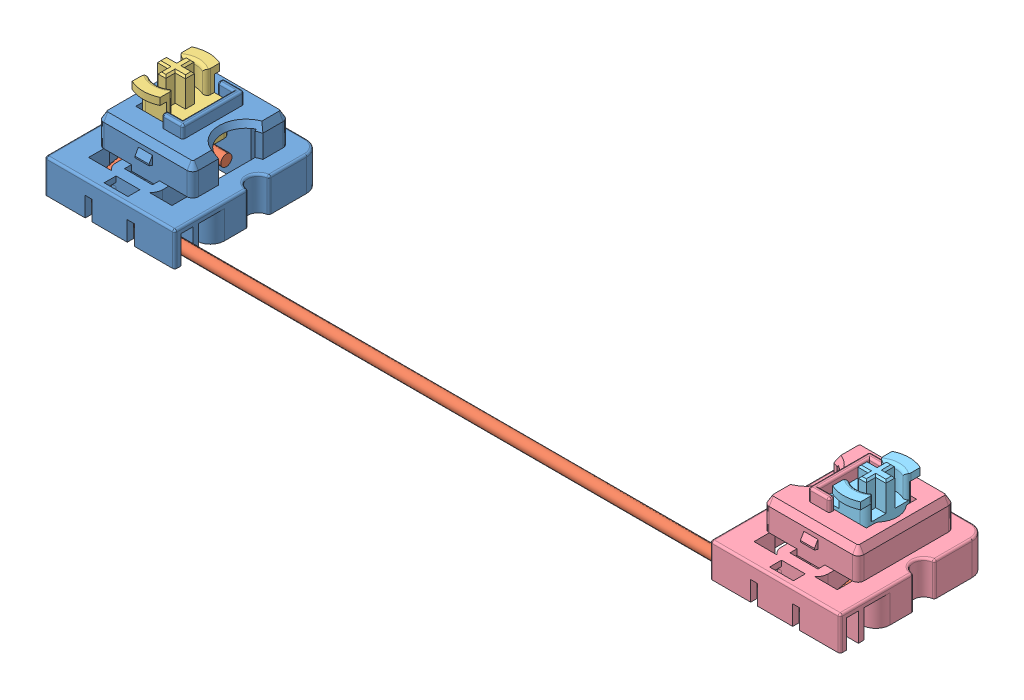
SolidWorks assembly Stabilizers, configuration Default. Lengths in mm.
Overall size (113.55 13.31 20.85).
5 component instances, 5 part files, 13 mates.
Components (placement in the parent):
- Stabilizer Housing Left-4: Stabilizer Housing Left [Default] at (-18.6144 -12.306 -7.1662) size (18.55 10.8 20.85)
- Stabilizer Wire-2: Stabilizer Wire [Default] at (28.8856 -14.606 3.0838) x (1 0 0) z (0 -0.226827 0.973935) size (106 1.6 13.1)
- Stabilizer Plunger Left-1: Stabilizer Plunger Left [Default] at (-21.1144 -13.7975 -7.1662) size (6.4 10.8 9.4)
- Stabilizer Housing Right-1: Stabilizer Housing Right [Default] at (76.3856 -12.306 -7.1662) size (18.55 10.8 20.85)
- Stabilizer Plunger Right-1: Stabilizer Plunger Right [Default] at (78.8856 -13.7975 -7.1662) size (6.4 10.8 9.4)
Mates (geometry in assembly coordinates):
- Tangent2: tangent: plane of assembly; cylinder of assembly; plane of Stabilizer Housing Left-4 through (-18.6144 -13.806 -7.1662) normal (0 -1 0); cylinder of Stabilizer Wire-2 through (79.4856 -14.606 3.0838) axis (-1 0 0) radius 0.8
- Distance3: distance = 47.5 mm: plane of assembly; plane of assembly; plane of Stabilizer Wire-2 through (28.8856 -14.606 3.0838) normal (1 0 0); plane of Stabilizer Housing Left-4 through (-18.6144 -12.306 -7.1662) normal (1 0 0)
- Tangent3: tangent: plane of assembly; cylinder of assembly; plane of Stabilizer Housing Left-4 through (-9.3394 -34.8778 3.8838) normal (0 0 -1); cylinder of Stabilizer Wire-2 through (79.4856 -14.606 3.0838) axis (-1 0 0) radius 0.8
- Coincident1: coincident: plane of assembly; plane of assembly; plane of Stabilizer Housing Left-4 through (-18.6144 -12.306 -7.1662) normal (1 0 0); plane of Stabilizer Plunger Left-1 through (-18.6144 -13.7975 -7.1662) normal (1 0 0)
- Coincident2: coincident: plane of assembly; plane of assembly; plane of Stabilizer Housing Left-4 through (-18.6144 -12.306 -7.1662) normal (0 0 1); plane of Stabilizer Plunger Left-1 through (-21.1144 -13.7975 -7.1662) normal (0 0 1)
- Tangent5: tangent: cylinder of assembly; plane of assembly; cylinder of Stabilizer Wire-2 through (-21.7144 -11.9975 -8.1164) axis (1 0 0) radius 0.8; plane of Stabilizer Plunger Left-1 through (-23.1144 -12.7975 -7.1662) normal (0 1 0)
- Tangent6: tangent: cylinder of assembly; plane of assembly; cylinder of Stabilizer Wire-2 through (79.4856 -14.606 3.0838) axis (-1 0 0) radius 0.8; plane of Stabilizer Housing Right-1 through (76.3856 -13.806 -7.1662) normal (0 -1 0)
- Tangent7: tangent: cylinder of assembly; plane of assembly; cylinder of Stabilizer Wire-2 through (79.4856 -14.606 3.0838) axis (-1 0 0) radius 0.8; plane of Stabilizer Housing Right-1 through (67.1106 -34.8778 3.8838) normal (0 0 -1)
- Distance5: distance = 47.5 mm: plane of assembly; plane of assembly; plane of Stabilizer Housing Right-1 through (76.3856 -12.306 -7.1662) normal (1 0 0); plane of Stabilizer Wire-2 through (28.8856 -14.606 3.0838) normal (1 0 0)
- Coincident9: coincident: plane of assembly; plane of assembly; plane of Stabilizer Housing Right-1 through (76.3856 -12.306 -7.1662) normal (0 0 1); plane of Stabilizer Plunger Right-1
- Coincident11: coincident: plane of assembly; plane of assembly; plane of Stabilizer Housing Right-1 through (76.3856 -12.306 -7.1662) normal (1 0 0); plane of Stabilizer Plunger Right-1
- Tangent8: tangent: cylinder of assembly; plane of assembly; cylinder of Stabilizer Wire-2 through (72.6356 -11.9975 -8.1164) axis (1 0 0) radius 0.8; plane of Stabilizer Plunger Right-1 through (80.8856 -12.7975 -7.1662) normal (0 1 0)
- Coincident12: coincident: plane of assembly; plane of assembly; plane of Stabilizer Housing Left-4 through (-18.6144 -12.306 -7.1662) normal (0 1 0); plane of Stabilizer Housing Right-1 through (76.3856 -12.306 -7.1662) normal (0 1 0)
